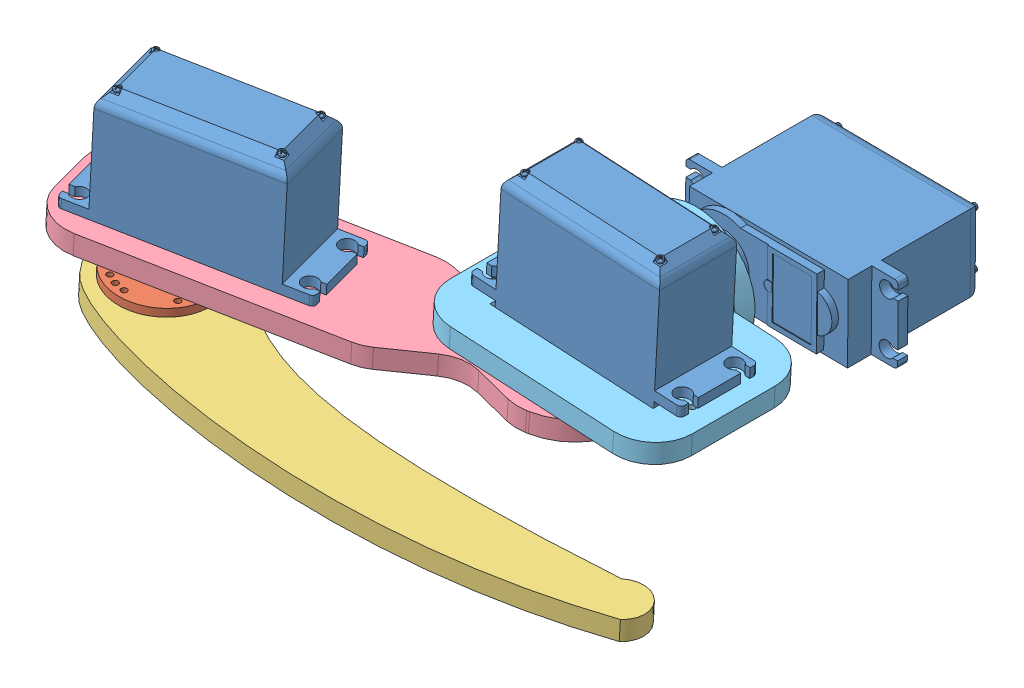
SolidWorks assembly right_leg, configuration Default. Lengths in mm.
Overall size (153.81 67.45 169.63).
9 component instances, 5 part files, 18 mates.
Components (placement in the parent):
- Standard Servo-1: Standard Servo [Default] at (-164.9949 41.2865 51.0885) x (-0.966756 0.053687 0.250002) z (0.249618 -0.013862 0.968245) size (53.74 42.63 19.57)
- Horn-1: Horn [Default] at (-178.6364 -2.1239 52.3374) x (-0.96331 0.053496 -0.263005) z (-0.2626 0.014583 0.964795) size (24 5 24)
- leg_3-1: leg_3 [Default] at (-178.9137 -7.1162 52.3374) x (-0.692538 0.038459 -0.720355) z (0.055448 0.998462 0) size (110.29 105.51 5)
- leg_2-1: leg_2 [Default] at (-104.7434 8.534 17.7694) x (0.966756 -0.053687 -0.250002) z (-0.055448 -0.998462 0) size (120 30 5)
- Standard Servo-2: Standard Servo [Default] at (-82.5781 51.471 32.5966) x (-0.998462 0.055448 0) z (0 0 1) size (53.74 42.63 19.57)
- Horn-2: Horn [Default] at (-96.1758 8.0582 31.0024) x (-0.993223 0.055157 0.102306) z (0.102149 -0.005673 0.994753) size (24 5 24)
- leg_1-1: leg_1 [Default] at (-115.137 36.2229 6.2174) x (-0.998462 0.055448 0) z (0 0 1) size (61.5 30 46)
- Standard Servo-3: Standard Servo [Default] at (-78.3263 21.2733 -37.8826) x (-0.999962 0.008727 0) z (0.008727 0.999962 0) size (53.74 42.63 19.57)
- Horn-3: Horn [Default] at (-89.5094 19.7766 6.2174) x (0.993551 -0.113383 0) z (-0.113383 -0.993551 0) size (24 5 24)
Mates (geometry in assembly coordinates):
- Concentric9: concentric: cylinder of assembly; cylinder of assembly; cylinder of Standard Servo-3 through (-89.5094 19.7766 -2.2826) axis (0 0 1) radius 1.27; cylinder of Horn-3 through (-89.5094 19.7766 4.7174) axis (0 0 -1) radius 3
- Coincident19: coincident: plane of assembly; plane of assembly; plane of Standard Servo-3 through (-89.5094 19.7766 4.7174) normal (0 0 1); plane of Horn-3 through (-89.5094 19.7766 4.7174) normal (0 0 -1)
- Concentric10: concentric: cylinder of assembly; cylinder of assembly; cylinder of leg_1-1 through (-89.5094 19.7766 10.2174) axis (0 0 -1) radius 3.25; cylinder of Horn-3 through (-89.5094 19.7766 5.7174) axis (0 0 1) radius 3
- Coincident20: coincident: plane of assembly; plane of assembly; plane of leg_1-1 through (-115.137 36.2229 6.2174) normal (0 0 -1); plane of Horn-3 through (-101.4321 21.1372 6.2174) normal (0 0 1)
- Coincident21: coincident: plane of assembly; plane of assembly; plane of Standard Servo-2 through (-106.1693 17.3566 21.2174) normal (-0.998462 0.055448 0); plane of leg_1-1 through (-106.1227 18.1953 42.2174) normal (0.998462 -0.055448 0)
- Coincident22: coincident: plane of Standard Servo-2 through (-65.9113 15.1209 21.2174) normal (0 0 -1); plane of leg_1-1 through (-64.6865 15.8942 21.2174) normal (0 0 1)
- Coincident23: coincident: plane of Standard Servo-2 through (-112.5451 23.5597 40.7874) normal (-0.055448 -0.998462 0); plane of leg_1-1 through (-54.4247 20.3321 52.2174) normal (0.055448 0.998462 0)
- Concentric11: concentric: cylinder of Standard Servo-2 through (-95.7045 16.5451 31.0024) axis (-0.055448 -0.998462 0) radius 1.27; cylinder of Horn-2 through (-96.0927 9.5559 31.0024) axis (0.055448 0.998462 0) radius 3
- Coincident24: coincident: plane of Standard Servo-2 through (-96.0927 9.5559 31.0024) normal (-0.055448 -0.998462 0); plane of Horn-2 through (-96.0927 9.5559 31.0024) normal (0.055448 0.998462 0)
- Coincident25: coincident: plane of leg_2-1 through (-96.1758 8.0582 31.0024) normal (0.055448 0.998462 0); plane of Horn-2 through (-84.2572 7.3963 29.7747) normal (-0.055448 -0.998462 0)
- Concentric12: concentric: cylinder of leg_2-1 through (-96.4531 3.0659 31.0024) axis (0.055448 0.998462 0) radius 2.5; cylinder of Horn-2 through (-96.1481 8.5574 31.0024) axis (-0.055448 -0.998462 0) radius 3
- Coincident26: coincident: plane of Standard Servo-1 through (-190.7396 7.2916 45.4865) normal (-0.966756 0.053687 0.250002); plane of leg_2-1 through (-185.7987 8.0275 64.4351) normal (0.966756 -0.053687 -0.250002)
- Coincident27: coincident: plane of Standard Servo-1 through (-146.875 4.8557 54.355) normal (0.249618 -0.013862 0.968245); plane of leg_2-1 through (-185.7987 8.0275 64.4351) normal (-0.249618 0.013862 -0.968245)
- Coincident28: coincident: plane of Standard Servo-1 through (-144.94 10.7662 33.7289) normal (-0.055448 -0.998462 0); plane of leg_2-1 through (-96.1758 8.0582 31.0024) normal (0.055448 0.998462 0)
- Concentric13: concentric: cylinder of Standard Servo-1 through (-178.1651 6.363 52.3374) axis (-0.055448 -0.998462 0) radius 1.27; cylinder of Horn-1 through (-178.6364 -2.1239 52.3374) axis (-0.055448 -0.998462 0) radius 1.4
- Coincident29: coincident: plane of Standard Servo-1 through (-178.5533 -0.6262 52.3374) normal (-0.055448 -0.998462 0); plane of Horn-1 through (-178.5533 -0.6262 52.3374) normal (0.055448 0.998462 0)
- Coincident30: coincident: plane of Horn-1 through (-167.0767 -2.7659 55.4934) normal (-0.055448 -0.998462 0); plane of leg_3-1 through (-139.7691 -4.2824 76.043) normal (0.055448 0.998462 0)
- Concentric14: concentric: cylinder of Horn-1 through (-178.6364 -2.1239 52.3374) axis (-0.055448 -0.998462 0) radius 1.4; cylinder of leg_3-1 through (-178.9137 -7.1162 52.3374) axis (0.055448 0.998462 0) radius 3.25
